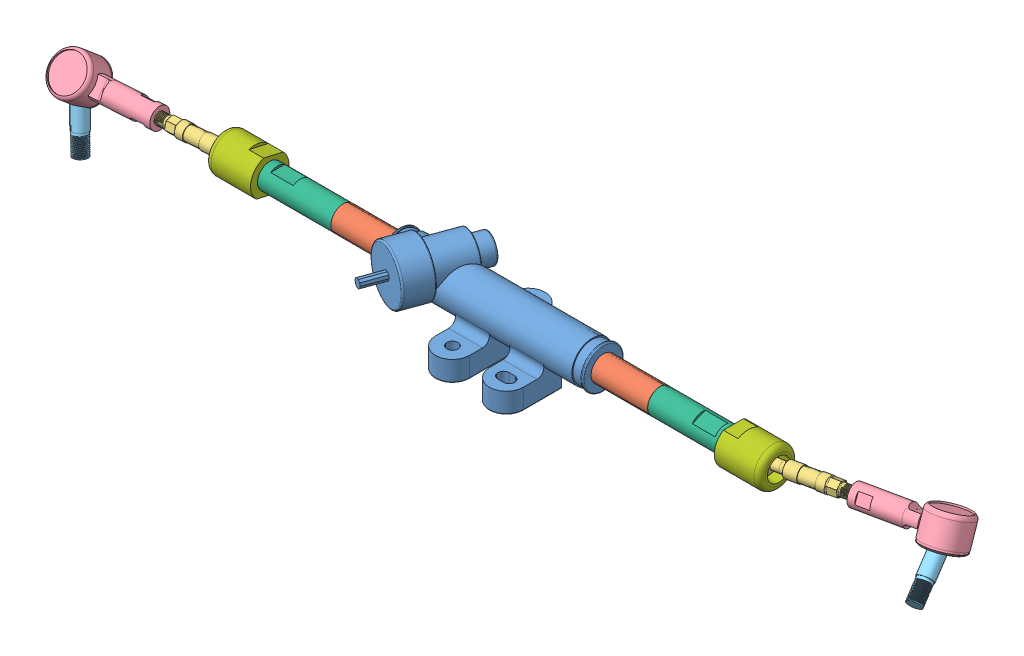
SolidWorks assembly steering assembly, configuration Default. Lengths in mm.
Overall size (787.33 98.91 107.55).
12 component instances, 7 part files, 21 mates.
Components (placement in the parent):
- prebuilt housing-1: prebuilt housing [Default] at (-22.0598 82.7728 134.0833) size (180 70.59 106.9)
- prebuilt rack-1: prebuilt rack [Default] at (207.9402 82.7728 134.0833) x (0 0.567124 0.823632) z (0 -0.823632 0.567124) size (22 312 22)
- prebuilt ball joint-1: prebuilt ball joint [Default] at (307.6464 83.1181 131.9326) x (0.071668 0.835779 0.544369) z (0.158838 -0.548371 0.821012) size (25 124 25)
- prebuilt ball joint-2: prebuilt ball joint [Default] at (-171.9431 82.2373 134.3416) x (-0.00868 -0.262981 -0.964762) z (0.046761 -0.963849 0.262312) size (25 124 25)
- prebuilt ball joint end-1: prebuilt ball joint end [Default] at (435.4862 98.9353 103.4029) x (-0.141765 -0.447158 -0.883149) z (-0.9847 -0.027626 0.172054) size (35 27 87.5)
- prebuilt ball joint end-2: prebuilt ball joint end [Default] at (-302.9701 85.2872 147.3534) x (0.046084 -0.764308 0.643203) z (0.998868 0.042837 -0.020664) size (35 27 87.5)
- ball end joint conection piece-1: ball end joint conection piece [Default] at (448.1924 91.453 109.9698) x (0.253129 -0.555984 0.791712) z (0.357201 -0.706825 -0.610578) size (65.5 25 25)
- ball end joint conection piece-2: ball end joint conection piece [Default] at (-290.9018 77.426 132.7227) x (0.166318 -0.973362 0.157812) z (-0.257576 -0.197369 -0.945886) size (65.5 25 25)
- extender-1: extender [Default] at (272.9402 82.7728 134.0833) x (0 0.924347 0.381554) z (0 -0.381554 0.924347) size (21.8 81.01 21.8)
- extender-2: extender [Default] at (-137.0598 82.7728 134.0833) x (0 -0.999985 -0.005515) z (0 -0.005515 0.999985) size (21.8 81.01 21.8)
- rackBallEnd-1: rackBallEnd [Default] at (-7.0598 82.7728 134.0833) x (0 -1 0) z (0 0 1) size (34 40.37 34)
- rackBallEnd-2: rackBallEnd [Default] at (142.9402 82.7728 134.0833) x (0 0.975815 -0.218598) z (0 0.218598 0.975815) size (34 40.37 34)
Mates (geometry in assembly coordinates):
- Concentric1: concentric anti-aligned: cylinder of prebuilt housing-1 through (157.9402 82.7728 134.0833) axis (-1 0 0) radius 11; cylinder of prebuilt rack-1 through (-72.0598 82.7728 134.0833) axis (1 0 0) radius 11
- Concentric4: concentric anti-aligned: cylinder of prebuilt ball joint-2 through (-213.8956 80.4382 135.2094) axis (-0.998868 -0.042837 0.020664) radius 6; circle of prebuilt ball joint end-2
- Concentric5: concentric anti-aligned: circle of prebuilt ball joint-1; circle of prebuilt ball joint end-1
- Concentric6: concentric: sphere of prebuilt ball joint end-1; sphere of ball end joint conection piece-1
- Concentric7: concentric: sphere of prebuilt ball joint end-2; sphere of ball end joint conection piece-2
- Parallel1: parallel anti-aligned: line of prebuilt ball joint end-2 through (-336.8968 81.5108 129.2357) axis (-0.023858 0.101359 -0.994564); line of ball end joint conection piece-2 through (-337.9976 86.1875 83.3467) axis (0.023858 -0.101359 0.994564)
- Concentric8: concentric anti-aligned: circle of prebuilt rack-1; circle of extender-2
- Coincident3: coincident anti-aligned: plane of prebuilt rack-1 through (-72.0598 95.1403 107.9625) normal (-1 0 0); plane of extender-2 through (-72.0598 82.7728 134.0833) normal (1 0 0)
- Concentric9: concentric anti-aligned: circle of prebuilt rack-1; circle of extender-1
- Coincident4: coincident anti-aligned: plane of prebuilt rack-1 through (207.9402 95.1403 107.9625) normal (1 0 0); plane of extender-1 through (207.9402 82.7728 134.0833) normal (-1 0 0)
- Concentric10: concentric anti-aligned: circle of extender-2; circle of rackBallEnd-2
- Coincident5: coincident anti-aligned: plane of extender-2 through (-137.0598 82.7728 134.0833) normal (-1 0 0); plane of rackBallEnd-2 through (-137.0598 82.7728 134.0833) normal (1 0 0)
- Concentric11: concentric anti-aligned: circle of extender-1; circle of rackBallEnd-1
- Coincident6: coincident anti-aligned: plane of extender-1 through (272.9402 82.7728 134.0833) normal (1 0 0); plane of rackBallEnd-1 through (272.9402 82.7728 134.0833) normal (-1 0 0)
- Concentric12: concentric: sphere of prebuilt ball joint-1; sphere of rackBallEnd-1
- Concentric13: concentric: sphere of prebuilt ball joint-2; sphere of rackBallEnd-2
- Coincident7: coincident: point of prebuilt housing-1; point of prebuilt rack-1
- Parallel2: parallel anti-aligned: plane of prebuilt ball joint-2 through (-222.8854 80.0526 135.3954) normal (-0.998868 -0.042837 0.020664); plane of prebuilt ball joint end-2 through (-232.889 79.5114 135.469) normal (0.998868 0.042837 -0.020664)
- Parallel3: parallel anti-aligned: plane of prebuilt ball joint-1 through (357.8661 84.527 123.1579) normal (0.9847 0.027626 -0.172054); plane of prebuilt ball joint end-1 through (367.9391 84.8096 121.3978) normal (-0.9847 -0.027626 0.172054)
- Lock1: lock: unknown of prebuilt ball joint-1; unknown of prebuilt ball joint end-1
- Lock2: lock: unknown of prebuilt ball joint-2; unknown of prebuilt ball joint end-2
